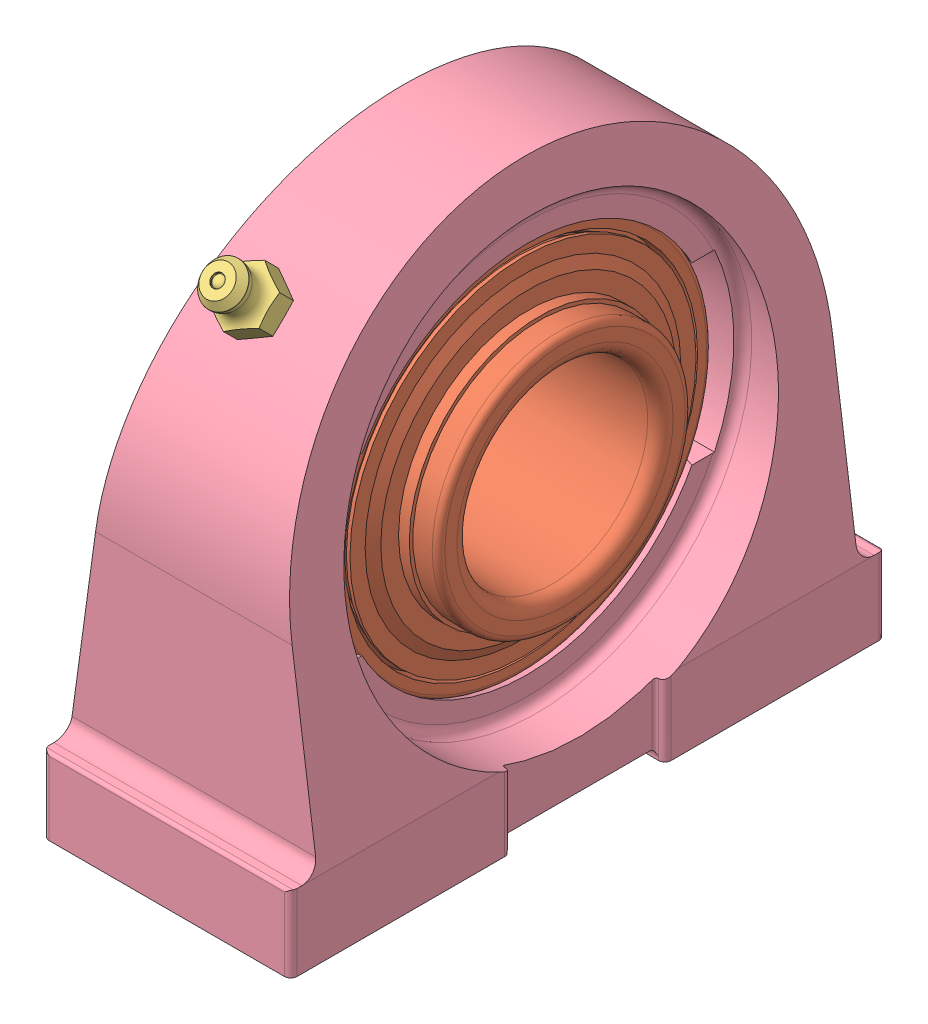
SolidWorks assembly SKF_UCPA 206, configuration Default. Lengths in mm.
Overall size (41.71 84.01 93.51).
11 component instances, 4 part files, 0 mates.
Components (placement in the parent):
- 30-62-38.1-18-ucpa--9.525-46.5-1: 30-62-38.1-18-ucpa--9.525-46.5 [Default] at (0 39.6902 16.4402) x (1 0 0) z (0 0 -1) size (9.53 9.52 9.53)
- 30-62-38.1-18-ucpa--9.525-46.5-2: 30-62-38.1-18-ucpa--9.525-46.5 [Default] at (0 23.25 23.25) x (1 0 0) z (0 0 -1) size (9.53 9.52 9.53)
- 30-62-38.1-18-ucpa--9.525-46.5-3: 30-62-38.1-18-ucpa--9.525-46.5 [Default] at (0 6.8098 16.4402) x (1 0 0) z (0 0 -1) size (9.53 9.52 9.53)
- 30-62-38.1-18-ucpa--9.525-46.5-4: 30-62-38.1-18-ucpa--9.525-46.5 [Default] x (1 0 0) z (0 0 -1) size (9.53 9.52 9.53)
- 30-62-38.1-18-ucpa--9.525-46.5-5: 30-62-38.1-18-ucpa--9.525-46.5 [Default] at (0 6.8098 -16.4402) x (1 0 0) z (0 0 -1) size (9.53 9.52 9.53)
- 30-62-38.1-18-ucpa--9.525-46.5-6: 30-62-38.1-18-ucpa--9.525-46.5 [Default] at (0 23.25 -23.25) x (1 0 0) z (0 0 -1) size (9.53 9.52 9.53)
- 30-62-38.1-18-ucpa--9.525-46.5-7: 30-62-38.1-18-ucpa--9.525-46.5 [Default] at (0 39.6902 -16.4402) x (1 0 0) z (0 0 -1) size (9.53 9.52 9.53)
- 30-62-38.1-18-ucpa--9.525-46.5-8: 30-62-38.1-18-ucpa--9.525-46.5 [Default] at (0 46.5 0) x (1 0 0) z (0 0 -1) size (9.53 9.52 9.53)
- UC 206-39.862-b-1: UC 206-39.862-b [Default] x (-1 0 0) z (0 0 -1) size (38.1 62 62)
- 1_4-28 UNF-1: 1_4-28 UNF [Default] at (-2.5 29.8399 29.8399) x (1 0 0) z (0 -0.707107 0.707107) size (9.18 13.9 9.18)
- PA 206 -h-1: PA 206 -h [Domyślna] x (0 0 1) z (-1 0 0) size (93.51 84.01 39.21)
